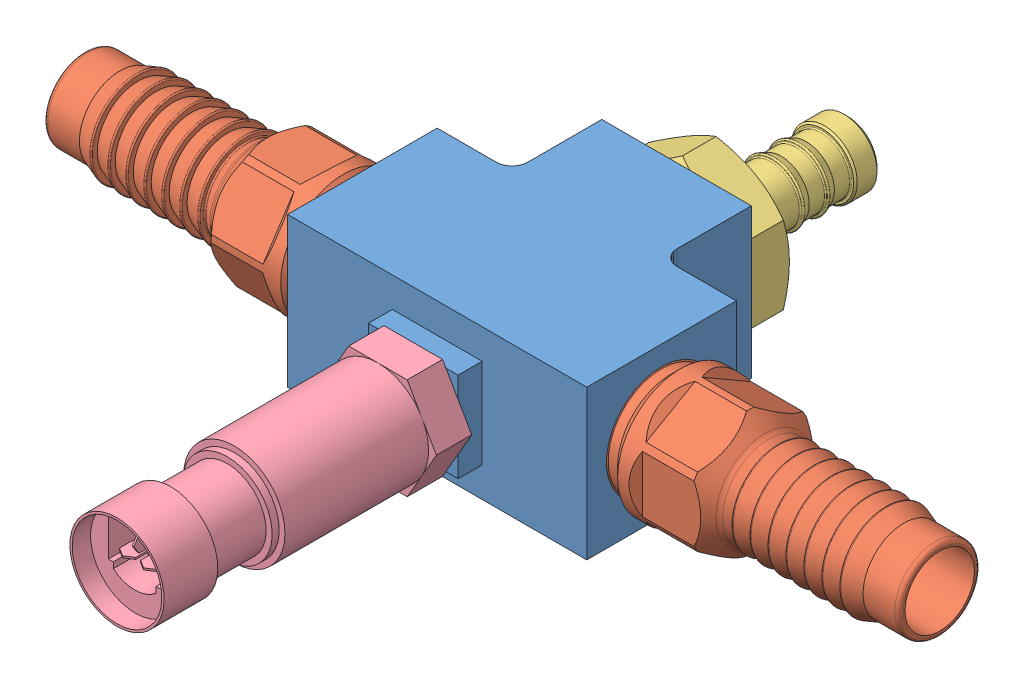
SolidWorks assembly Tee Adapter Subassembly, configuration Default. Lengths in mm.
Overall size (181.56 33 155.08).
5 component instances, 4 part files, 8 mates.
Components (placement in the parent):
- EN10113-AA-Aluminum Tee-2: EN10113-AA-Aluminum Tee [Default] at origin size (63.5 31.75 55.88)
- EN10111-AA-0.75in Easy-Fit Barbed Hose Fitting (5363K52)-1: EN10111-AA-0.75in Easy-Fit Barbed Hose Fitting (5363K52) [5363K52] at (51.0945 15.875 0) x (0 0 -1) z (1 0 0) size (26.67 28.88 79.38)
- EN10111-AA-0.75in Easy-Fit Barbed Hose Fitting (5363K52)-2: EN10111-AA-0.75in Easy-Fit Barbed Hose Fitting (5363K52) [5363K52] at (-51.0945 15.875 0) x (0 -0.99851 0.054572) z (-1 0 0) size (26.67 28.88 79.38)
- EN10112-AA-Zinc-Plated Steel Barbed Hose Fitting (5350K43)-1: EN10112-AA-Zinc-Plated Steel Barbed Hose Fitting (5350K43) [5350K43] at (0 15.875 -44.577) x (-1 0 0) z (0 0 -1) size (28.57 33 55.88)
- EN-10202-AA-Pressure and Temperature Transducer, Transducers Direct-1: EN-10202-AA-Pressure and Temperature Transducer, Transducers Direct [Default] at (0 15.875 10.655) x (1 0 0) z (0 -1 0) size (24.83 73.18 21.5)
Mates (geometry in assembly coordinates):
- Concentric1: concentric aligned: cylinder of EN10111-AA-0.75in Easy-Fit Barbed Hose Fitting (5363K52)-1 through (90.782 15.875 0) axis (1 0 0) radius 7.366; cylinder of Aluminum Tee-2 through (31.75 15.875 0) axis (1 0 0) radius 11.7079
- Coincident1: coincident anti-aligned: plane of Aluminum Tee-2 through (31.75 31.75 0) normal (1 0 0); circle of EN10111-AA-0.75in Easy-Fit Barbed Hose Fitting (5363K52)-1
- Concentric2: concentric anti-aligned: cylinder of Aluminum Tee-2 through (31.75 15.875 0) axis (1 0 0) radius 11.7079; cylinder of EN10111-AA-0.75in Easy-Fit Barbed Hose Fitting (5363K52)-2 through (-90.782 15.875 0) axis (-1 0 0) radius 7.366
- Coincident2: coincident anti-aligned: plane of Aluminum Tee-2 through (-31.75 31.75 0) normal (-1 0 0); circle of EN10111-AA-0.75in Easy-Fit Barbed Hose Fitting (5363K52)-2
- Concentric3: concentric anti-aligned: cylinder of Aluminum Tee-2 through (0 15.875 -34.925) axis (0 0 -1) radius 11.7079; cylinder of EN10112-AA-Zinc-Plated Steel Barbed Hose Fitting (5350K43)-1 through (0 15.875 -44.577) axis (0 0 1) radius 4.826
- Coincident3: coincident anti-aligned: plane of Aluminum Tee-2 through (0 31.75 -34.925) normal (0 0 -1); plane of EN10112-AA-Zinc-Plated Steel Barbed Hose Fitting (5350K43)-1 through (0 32.3728 -34.925) normal (0 0 1)
- Concentric4: concentric anti-aligned: cylinder of Aluminum Tee-2 through (0 15.875 20.955) axis (0 0 1) radius 5.5563; cylinder of EN-10202-AA-Pressure and Temperature Transducer, Transducers Direct-1 through (0 15.875 20.955) axis (0 0 -1) radius 5.1435
- Coincident4: coincident anti-aligned: plane of Aluminum Tee-2 through (0 0 20.955) normal (0 0 1); plane of EN-10202-AA-Pressure and Temperature Transducer, Transducers Direct-1 through (0 15.875 20.955) normal (0 0 -1)
